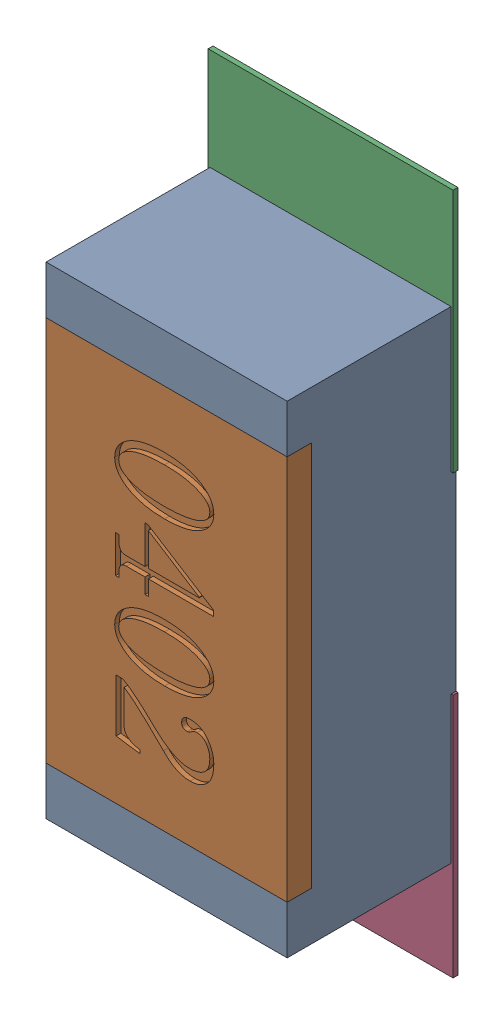
SolidWorks assembly R67, configuration Défaut. Lengths in mm.
Overall size (0.51 1.42 0.35).
5 component instances, 2 part files, 0 mates.
Components (placement in the parent):
- R0402-1: R0402 [Défaut] at (42.7227 -32.3178 0) x (0 -1 0) z (0 0 1) size (1 0.5 0.35)
- 6504207776-1: 6504207776 [Défaut] at (42.7228 -31.8607 0) size (0.51 0.51 0.01)
  - Extruded-1: Extruded [Défaut] at origin size (0.51 0.51 0.01)
- 6504207776-2: 6504207776 [Défaut] at (42.7228 -32.7678 0) size (0.51 0.51 0.01)
  - Extruded-1: Extruded [Défaut] at origin size (0.51 0.51 0.01)
